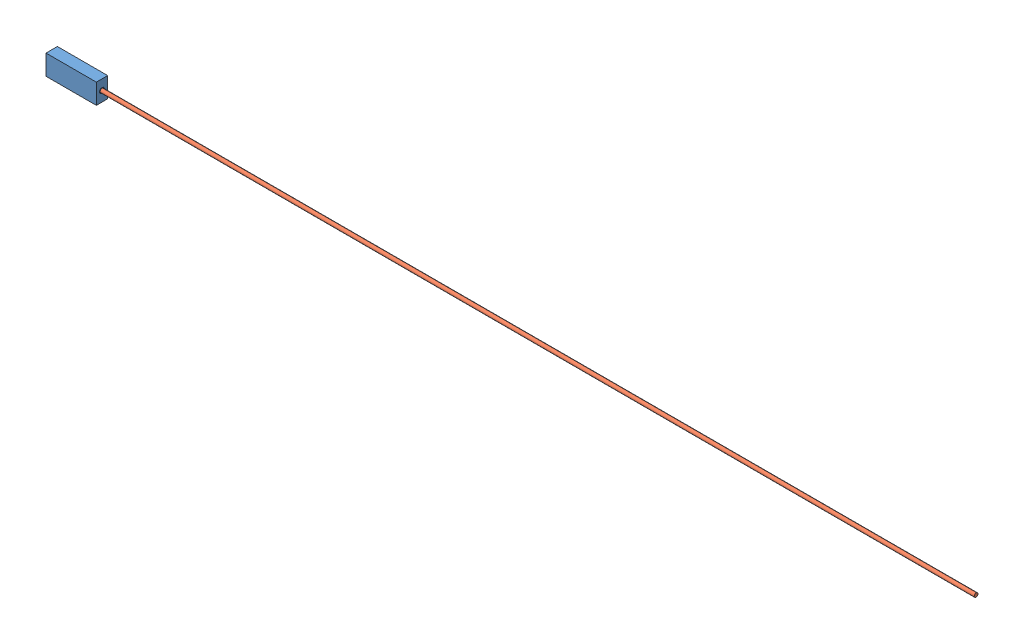
SolidWorks assembly Harness_8-CABLE_HARNESSING_ASSEMBLY-001, configuration AnnotateFlattenedRoute1 - Default. Lengths in mm.
Overall size (183.61 4 2.26).
3 component instances, 3 part files, 1 mates.
Components (placement in the parent):
- 01_PIN_CONNECTOR-1: 01_PIN_CONNECTOR [Default] at (-10 2 -1.125) x (0 0 1) z (1 0 0) size (2.26 4 20)
- Cable^Harness_8-CABLE_HARNESSING_ASSEMBLY-001-1: Cable^Harness_8-CABLE_HARNESSING_ASSEMBLY-001 [Default] at origin size (8.23 101 116.42) (suppressed, hidden, virtual)
- Flattened_Cable^Harness_8-CABLE_HARNESSING_ASSEMBLY-001-1: Flattened_Cable^Harness_8-CABLE_HARNESSING_ASSEMBLY-001 [Default] at origin (virtual)
Mates (geometry in assembly coordinates):
- Coincident97: coincident anti-aligned: plane of STACK_SHELVES-2/FAKE_PCB-4 through (107.6729 145.9 -83.7357) normal (0 1 0); plane of 01_PIN_CONNECTOR-1 through (52.8821 145.9 -43.9608) normal (0 -1 0)
